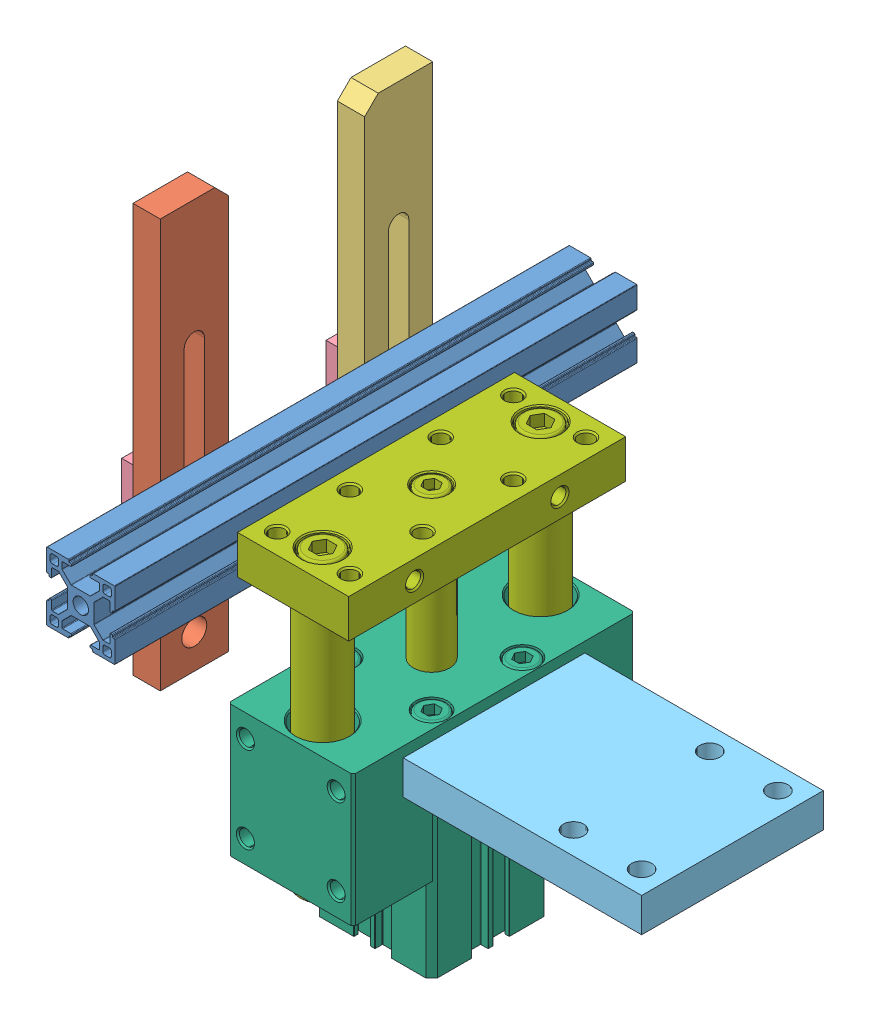
SolidWorks assembly 顶料气缸, configuration 默认. Lengths in mm.
Overall size (204 270 230).
8 component instances, 7 part files, 21 mates.
Components (placement in the parent):
- 铝型材230-1: 铝型材230 [默认<按加工>] at (778.7359 1167.6792 -158.4794) x (0 0 1) z (0 1 0) size (230 30 30)
- 顶料块尼龙-1: 顶料块尼龙 [默认] at (751.7359 1192.6792 6.5206) x (0 0 -1) z (1 0 0) size (30 180 12)
- 顶料块尼龙1-1: 顶料块尼龙1 [默认] at (751.7359 1192.6792 -83.4794) x (0 0 -1) z (1 0 0) size (30 180 12)
- 连接块30x5-1: 连接块30x5 [默认] at (746.7359 1167.9292 -83.4794) x (0 1 0) z (1 0 0) size (30 30 5)
- 气缸连接板-1: 气缸连接板 [默认] at (898.2359 1090.6792 -43.4794) x (0 0 -1) z (0 1 0) size (80 105 53.19)
- 连接块30x5-2: 连接块30x5 [默认] at (746.7359 1167.9292 6.5206) x (0 1 0) z (1 0 0) size (30 30 5)
- _JCB-40x50_B.stp-1: _JCB-40x50_B.stp [默认] at (818.2359 1110.1792 -43.4794) x (0 0 -1) z (0 1 0) size (124 59.5 97.5)
- _JCB-40x50_R.stp-1: _JCB-40x50_R.stp [默认] at (818.2359 1155.1792 -43.4794) x (0 0 -1) z (0 1 0) size (122 49 129)
Mates (geometry in assembly coordinates):
- 距离1: distance = 7 mm anti-aligned: plane of 高型连接块30x5-2 through (751.7359 1182.9292 21.5206) normal (0 1 0); plane of 高型一字铝型材230-1 through (766.2359 1175.9292 71.5206) normal (0 -1 0)
- 重合2: coincident anti-aligned: plane of 高型一字铝型材230-1 through (763.7359 1162.1792 71.5206) normal (-1 0 0); plane of 高型顶料块1-1 through (763.7359 1192.6792 -83.4794) normal (1 0 0)
- 重合4: coincident aligned: plane of 高型连接块30x5-1 through (751.7359 1182.9292 -68.4794) normal (0 1 0); plane of 高型连接块30x5-2 through (751.7359 1182.9292 21.5206) normal (0 1 0)
- 重合6: coincident anti-aligned: plane of 高型顶料块-1 through (751.7359 1192.6792 6.5206) normal (-1 0 0); plane of 高型连接块30x5-2 through (751.7359 1167.9292 6.5206) normal (1 0 0)
- 重合7: coincident aligned: plane of 高型顶料块1-1 through (763.7359 1282.6792 -98.4794) normal (0 0 -1); plane of 高型连接块30x5-1 through (751.7359 1152.9292 -98.4794) normal (0 0 -1)
- 重合8: coincident aligned: plane of 高型顶料块-1 through (763.7359 1282.6792 21.5206) normal (0 0 1); plane of 高型连接块30x5-2 through (751.7359 1152.9292 21.5206) normal (0 0 1)
- 距离6: distance = 50 mm aligned: plane of 高型顶料块-1 through (763.7359 1282.6792 21.5206) normal (0 0 1); plane of 高型一字铝型材230-1 through (774.6158 1173.7792 71.5206) normal (0 0 1)
- 距离7: distance = 60 mm anti-aligned: plane of 高型顶料块-1 through (763.7359 1282.6792 -8.4794) normal (0 0 -1); plane of 高型顶料块1-1 through (763.7359 1282.6792 -68.4794) normal (0 0 1)
- 重合9: coincident anti-aligned: plane of 高型顶料块1-1 through (751.7359 1192.6792 -83.4794) normal (-1 0 0); plane of 高型连接块30x5-1 through (751.7359 1167.9292 -83.4794) normal (1 0 0)
- LimitDistance1: limit distance = 49 mm anti-aligned: plane of _JCB-40x50_R.stp-1 through (818.2359 1159.1792 -43.4794) normal (0 -1 0); plane of _JCB-40x50_B.stp-1 through (818.2359 1110.1792 -43.4794) normal (0 1 0)
- 同心1: concentric aligned: cylinder of _JCB-40x50_B.stp-1 through (818.2359 1110.1792 4.5206) axis (0 -1 0) radius 11.5; cylinder of _JCB-40x50_R.stp-1 through (818.2359 1176.1792 4.5206) axis (0 -1 0) radius 10
- 同心2: concentric aligned: cylinder of _JCB-40x50_B.stp-1 through (818.2359 1110.1792 -91.4794) axis (0 -1 0) radius 11.5; cylinder of _JCB-40x50_R.stp-1 through (818.2359 1176.1792 -91.4794) axis (0 -1 0) radius 10
- 同心6: concentric aligned: cylinder of 气缸连接板-1 through (845.7359 1098.1792 -11.4794) axis (-1 0 0) radius 3.4; cylinder of _JCB-40x50_B.stp-1 through (845.7359 1098.1792 -11.4794) axis (-1 0 0) radius 4.188
- 同心7: concentric aligned: cylinder of 气缸连接板-1 through (845.7359 1098.1792 -75.4794) axis (-1 0 0) radius 3.4; cylinder of _JCB-40x50_B.stp-1 through (845.7359 1098.1792 -75.4794) axis (-1 0 0) radius 7
- 重合17: coincident anti-aligned: plane of 气缸连接板-1 through (845.7359 1105.6792 -3.4794) normal (-1 0 0); plane of _JCB-40x50_B.stp-1 through (845.7359 1052.1792 17.5206) normal (1 0 0)
- 宽度3: width anti-aligned: plane of 高型一字铝型材230-1; plane of 高型一字铝型材230-1; plane of _JCB-40x50_R.stp-1 through (842.7359 1159.1792 -104.4794) normal (0 0 -1); plane of _JCB-40x50_R.stp-1 through (793.7359 1159.1792 17.5206) normal (0 0 1)
- 重合19: coincident anti-aligned: plane of _JCB-40x50_R.stp-1 through (793.7359 1159.1792 -104.4794) normal (-1 0 0); plane of 高型一字铝型材230-1 through (793.7359 1173.1792 71.5206) normal (1 0 0)
- 宽度5: width: plane of 高型一字铝型材230-1; plane of 高型一字铝型材230-1; cylinder of _JCB-40x50_R.stp-1 through (813.6547 1167.6792 -75.4794) axis (-1 0 0) radius 3.3235
- 重合25: coincident anti-aligned: plane of 高型一字铝型材230-1 through (763.7359 1182.4792 71.5206) normal (-1 0 0); plane of 高型顶料块-1 through (763.7359 1192.6792 6.5206) normal (1 0 0)
- 距离9: distance = 100 mm aligned: plane of 高型顶料块-1 through (763.7359 1282.6792 21.5206) normal (0 1 0); plane of 高型一字铝型材230-1 through (793.5359 1182.6792 71.5206) normal (0 1 0)
- 距离10: distance = 100 mm aligned: plane of 高型顶料块1-1 through (763.7359 1282.6792 -68.4794) normal (0 1 0); plane of 高型一字铝型材230-1 through (773.2359 1182.6792 71.5206) normal (0 1 0)
